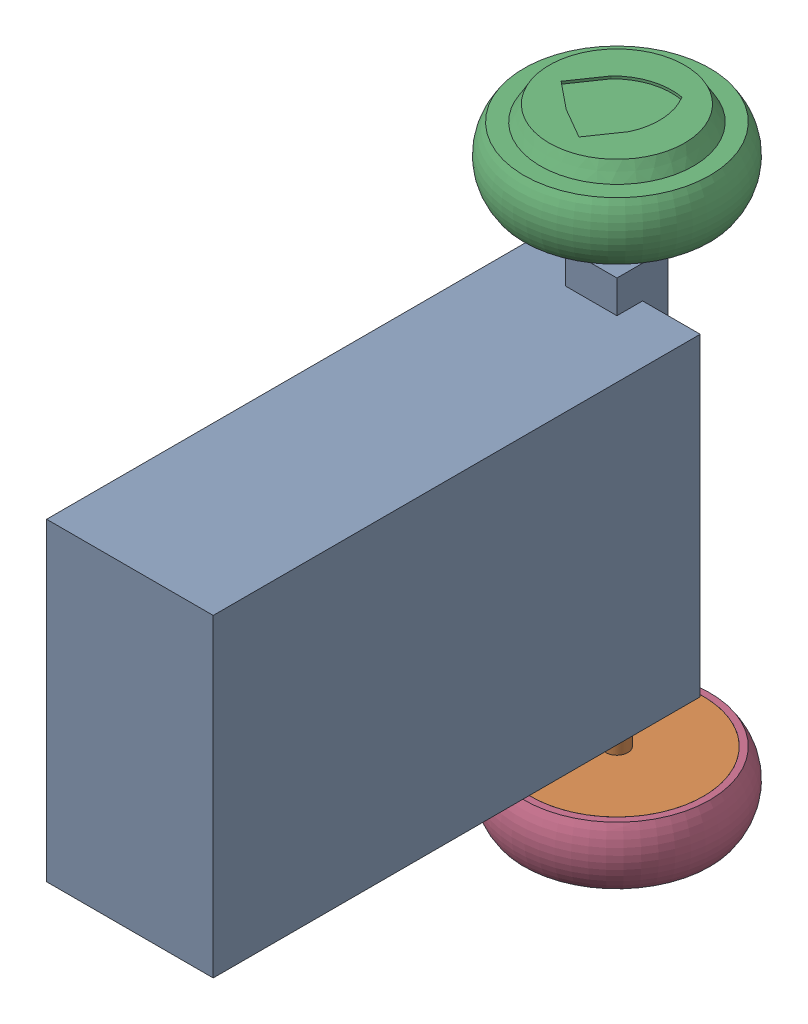
SolidWorks assembly assembly_simple, configuration Default. Lengths in mm.
Overall size (225.33 491 492.66).
4 component instances, 3 part files, 6 mates.
Components (placement in the parent):
- body-1: body [По умолчанию] at (399.9351 476.8405 -429.2262) size (130 296 400)
- axis_simple-1: axis_simple [По умолчанию] at (399.9351 476.8405 -619.2262) x (0.998323 0 0.057882) z (0 1 0) size (135 135 422)
- wheel_simple-1: wheel_simple [По умолчанию] at (399.9351 687.8405 -619.2262) x (-0.823983 0 -0.566615) z (0 1 0) size (159.5 159.5 57)
- wheel_simple-2: wheel_simple [По умолчанию] at (399.9351 265.8405 -619.2262) x (-0.738888 0 -0.673829) z (0 -1 0) size (159.5 159.5 57)
Mates (geometry in assembly coordinates):
- Концентричный1: concentric anti-aligned: cylinder of body-1 through (399.9351 648.8822 -619.2262) axis (0 -1 0) radius 8.5; cylinder of axis_simple-1 through (399.9351 476.8405 -619.2262) axis (0 1 0) radius 8.5
- Расстояние1: distance = 211 mm aligned: plane of axis_simple-1 through (402.945 265.8405 -671.139) normal (0 -1 0)
- Концентричный2: concentric aligned: cylinder of axis_simple-1 through (399.9351 476.8405 -619.2262) axis (0 1 0) radius 52; cylinder of wheel_simple-2 through (399.9351 236.3405 -619.2262) axis (0 1 0) radius 52
- Совпадение2: coincident anti-aligned: plane of axis_simple-1 through (403.8421 284.3405 -686.613) normal (0 -1 0); plane of wheel_simple-2 through (399.9351 284.3405 -619.2262) normal (0 1 0)
- Концентричный3: concentric aligned: cylinder of axis_simple-1 through (399.9351 476.8405 -619.2262) axis (0 -1 0) radius 52; cylinder of wheel_simple-1 through (399.9351 717.3405 -619.2262) axis (0 -1 0) radius 52
- Совпадение3: coincident anti-aligned: plane of axis_simple-1 through (403.8421 669.3405 -686.613) normal (0 1 0); plane of wheel_simple-1 through (399.9351 669.3405 -619.2262) normal (0 -1 0)
